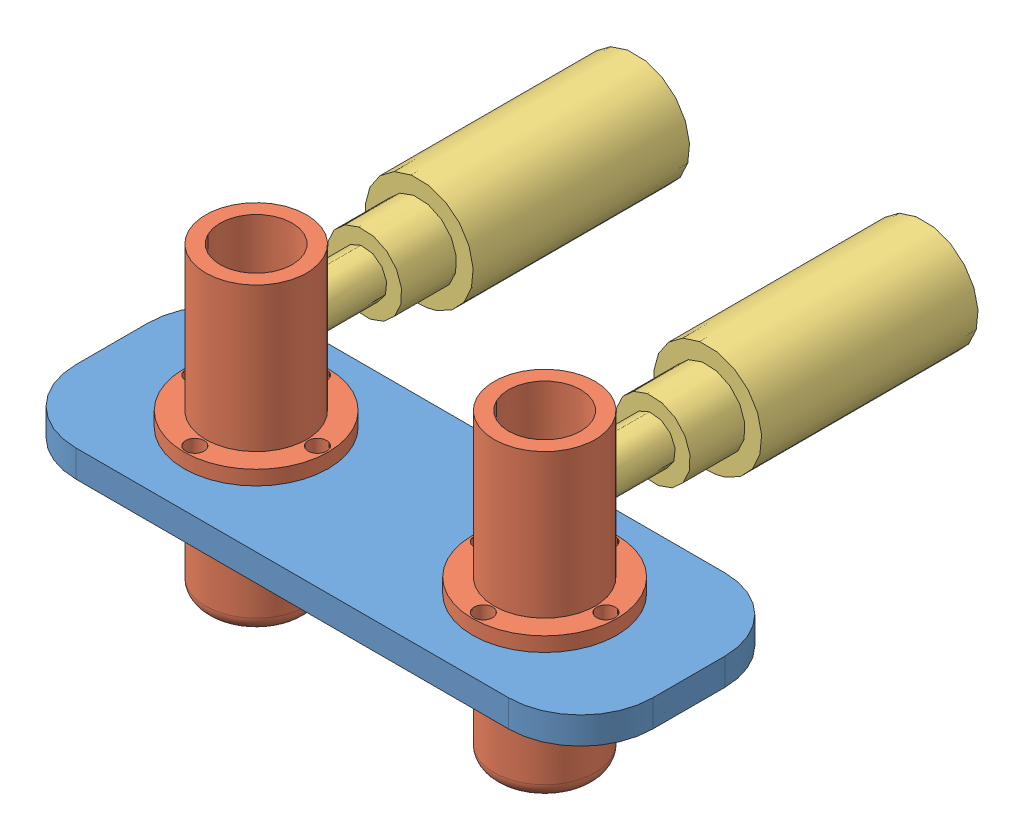
SolidWorks assembly Dropper, configuration Default. Lengths in mm.
Overall size (101.6 53.34 85.85).
5 component instances, 3 part files, 9 mates.
Components (placement in the parent):
- Dropper Plate-1: Dropper Plate [Default] at (-63.8113 9.7771 17.6557) size (101.6 4.76 38.1)
- Dropper Shell-1: Dropper Shell [Default] at (-38.4113 -10.8604 -1.3943) size (25.4 53.34 25.4)
- Dropper Shell-2: Dropper Shell [Default] at (12.3887 -10.8604 -1.3943) size (25.4 53.34 25.4)
- solenoid_dropper-1: solenoid_dropper [Default] at (12.3887 28.5096 -30.0963) x (0.148008 -0.988986 0) z (0 0 -1) size (19.05 19.05 66.8)
- solenoid_dropper-2: solenoid_dropper [Default] at (-38.4113 28.5096 -30.0963) x (0.148008 -0.988986 0) z (0 0 -1) size (19.05 19.05 66.8)
Mates (geometry in assembly coordinates):
- Concentric1: concentric aligned: cylinder of Dropper Plate-1 through (-38.4113 14.5396 -1.3943) axis (0 -1 0) radius 9.017; cylinder of Dropper Shell-1 through (-38.4113 14.5396 -1.3943) axis (0 -1 0) radius 8.89
- Concentric2: concentric anti-aligned: circle of Dropper Plate-1; cylinder of Dropper Shell-2 through (12.3887 14.5396 -1.3943) axis (0 -1 0) radius 8.89
- Concentric3: concentric aligned: circle of Dropper Plate-1; circle of Dropper Shell-2
- Coincident2: coincident anti-aligned: plane of Dropper Plate-1 through (-63.8113 14.5396 -20.4443) normal (0 1 0); plane of Dropper Shell-2 through (12.3887 14.5396 -1.3943) normal (0 -1 0)
- Coincident3: coincident aligned: circle of Dropper Plate-1; circle of Dropper Shell-1
- Concentric4: concentric anti-aligned: cylinder of Dropper Shell-2 through (12.3887 28.5096 -26.7943) axis (0 0 1) radius 4.1275; cylinder of solenoid_dropper-1 through (12.3887 28.5096 -1.3943) axis (0 0 -1) radius 3.9751
- Coincident4: coincident anti-aligned: plane of Dropper Plate-1 through (-63.8113 14.5396 -20.4443) normal (0 0 -1); plane of solenoid_dropper-1 through (12.3887 28.5096 -20.4443) normal (0 0 1)
- Concentric5: concentric anti-aligned: cylinder of Dropper Shell-1 through (-38.4113 28.5096 -26.7943) axis (0 0 1) radius 4.1275; cylinder of solenoid_dropper-2 through (-38.4113 28.5096 -1.3943) axis (0 0 -1) radius 3.9751
- Coincident5: coincident anti-aligned: plane of Dropper Plate-1 through (-63.8113 14.5396 -20.4443) normal (0 0 -1); plane of solenoid_dropper-2 through (-38.4113 28.5096 -20.4443) normal (0 0 1)
